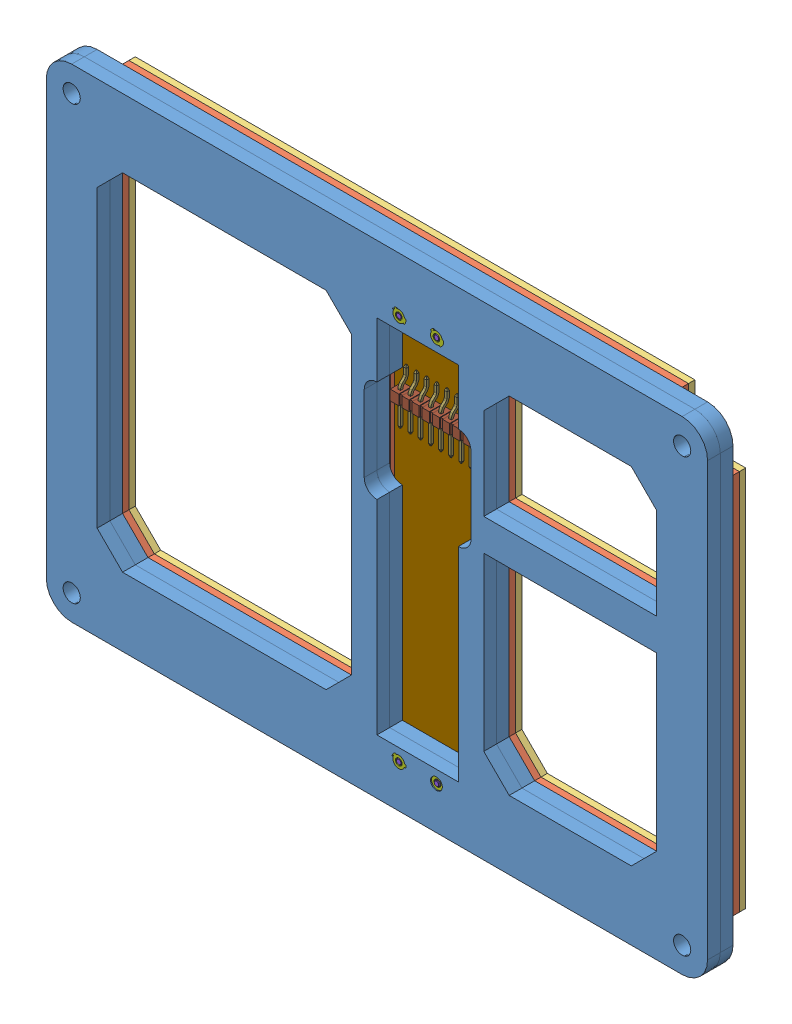
SolidWorks assembly IFEI Panel, configuration Default. Lengths in mm.
Overall size (165.1 120.65 15.95).
35 component instances, 12 part files, 29 mates.
Components (placement in the parent):
- IFEI Backplate-1: IFEI Backplate [Default] at (0 0 -3.175) size (165.1 120.65 3.17)
- IFEI Backplate-2: IFEI Backplate [Default] at origin size (165.1 120.65 3.17)
- IFEI Lightplate-1: IFEI Lightplate [Default] at (0 0 -6.35) x (-1 0 0) z (0 0 -1) size (165.1 120.65 1.59)
- IFEI Legend Plate-1: IFEI Legend Plate [Default] at (0 0 -7.9375) x (-1 0 0) z (0 0 -1) size (165.1 120.65 1.59)
- IFEI Button Bezel-1: IFEI Button Bezel [Default] at (0 0 -9.525) x (-1 0 0) z (0 0 -1) size (20.32 100.33 6.35)
- IFEI Button-1: IFEI Button [MODE] at (0 0 -12.7) x (-1 0 0) z (0 0 -1) size (15.49 9.14 3.17)
- IFEI Button Retainer-1: IFEI Button Retainer [Default] at (0 0 -11.1125) size (18.03 11.68 2.86)
- IFEI Button-2: IFEI Button [QTY] at (0 15.24 -12.7) x (-1 0 0) z (0 0 -1) size (15.49 9.14 3.17)
- IFEI Button-3: IFEI Button [ARROW] at (0 30.48 -12.7) x (-1 0 0) z (0 0 -1) size (15.49 9.14 3.17)
- IFEI Button-4: IFEI Button [ARROW] at (185.42 -154.178 -12.7) x (1 0 0) z (0 0 -1) size (15.49 9.14 3.17)
- IFEI Button-5: IFEI Button [ZONE] at (0 60.96 -12.7) x (-1 0 0) z (0 0 -1) size (15.49 9.14 3.17)
- IFEI Button-6: IFEI Button [ET] at (0 76.2 -12.7) x (-1 0 0) z (0 0 -1) size (15.49 9.14 3.17)
- IFEI Button Retainer-2: IFEI Button Retainer [Default] at (0 15.24 -11.1125) size (18.03 11.68 2.86)
- IFEI Button Retainer-3: IFEI Button Retainer [Default] at (0 30.48 -11.1125) size (18.03 11.68 2.86)
- IFEI Button Retainer-4: IFEI Button Retainer [Default] at (0 45.72 -11.1125) size (18.03 11.68 2.86)
- IFEI Button Retainer-5: IFEI Button Retainer [Default] at (0 60.96 -11.1125) size (18.03 11.68 2.86)
- IFEI Button Retainer-6: IFEI Button Retainer [Default] at (0 76.2 -11.1125) size (18.03 11.68 2.86)
- 93365A102__BRASS HEAT-SET INSERT FOR PLASTICS_0-80-1: 93365A102__BRASS HEAT-SET INSERT FOR PLASTICS_0-80 [Default] at (97.409 -110.0455 -3.175) x (-1 0 0) z (0 -1 0) size (3.58 3.01 3.58)
- 91249A024 - PHS, 0-80 X .50, 18-8, BLACK-OXIDE-1: 91249A024 - PHS, 0-80 X .50, 18-8, BLACK-OXIDE [91249A024] at (97.409 -110.0455 0) x (0.892261 0.451519 0) z (0 0 -1) size (2.95 2.95 13.84)
- 93365A102__BRASS HEAT-SET INSERT FOR PLASTICS_0-80-2: 93365A102__BRASS HEAT-SET INSERT FOR PLASTICS_0-80 [Default] at (88.011 -110.0455 0) x (0.27024 -0.962793 0) z (-0.962793 -0.27024 0) size (3.58 3.01 3.58)
- 91249A024 - PHS, 0-80 X .50, 18-8, BLACK-OXIDE-2: 91249A024 - PHS, 0-80 X .50, 18-8, BLACK-OXIDE [91249A024] at (88.011 -110.0455 0) x (0.615714 -0.78797 0) z (0 0 -1) size (2.95 2.95 13.84)
- 93365A102__BRASS HEAT-SET INSERT FOR PLASTICS_0-80-3: 93365A102__BRASS HEAT-SET INSERT FOR PLASTICS_0-80 [Default] at (97.409 -13.6525 0) x (0.414026 -0.910265 0) z (-0.910265 -0.414026 0) size (3.58 3.01 3.58)
- 91249A024 - PHS, 0-80 X .50, 18-8, BLACK-OXIDE-3: 91249A024 - PHS, 0-80 X .50, 18-8, BLACK-OXIDE [91249A024] at (97.409 -13.6525 0) x (0.488231 -0.872714 0) z (0 0 -1) size (2.95 2.95 13.84)
- 93365A102__BRASS HEAT-SET INSERT FOR PLASTICS_0-80-4: 93365A102__BRASS HEAT-SET INSERT FOR PLASTICS_0-80 [Default] at (88.011 -13.6525 0) x (-0.983471 -0.181065 0) z (-0.181065 0.983471 0) size (3.58 3.01 3.58)
- 91249A024 - PHS, 0-80 X .50, 18-8, BLACK-OXIDE-4: 91249A024 - PHS, 0-80 X .50, 18-8, BLACK-OXIDE [91249A024] at (88.011 -13.6525 0) x (0.728364 0.685191 0) z (0 0 -1) size (2.95 2.95 13.84)
- IFEI PCB-1: IFEI PCB [Default] at (0 0 -6.35) x (-1 0 0) z (0 0 -1) size (24.32 104.33 1.59)
- GX06400 - SWITCH, DOME, SNAPTRON, 6.3mm DIA, 400gf-1: GX06400 - SWITCH, DOME, SNAPTRON, 6.3mm DIA, 400gf [Default] at (92.71 -99.949 -7.9375) x (-0.707107 -0.707107 0) z (0.707107 -0.707107 0) size (6.3 0.36 6.3)
- GX06400 - SWITCH, DOME, SNAPTRON, 6.3mm DIA, 400gf-2: GX06400 - SWITCH, DOME, SNAPTRON, 6.3mm DIA, 400gf [Default] at (92.71 -84.709 -7.9375) x (-0.707107 -0.707107 0) z (0.707107 -0.707107 0) size (6.3 0.36 6.3)
- GX06400 - SWITCH, DOME, SNAPTRON, 6.3mm DIA, 400gf-3: GX06400 - SWITCH, DOME, SNAPTRON, 6.3mm DIA, 400gf [Default] at (92.71 -69.469 -7.9375) x (-0.707107 -0.707107 0) z (0.707107 -0.707107 0) size (6.3 0.36 6.3)
- GX06400 - SWITCH, DOME, SNAPTRON, 6.3mm DIA, 400gf-4: GX06400 - SWITCH, DOME, SNAPTRON, 6.3mm DIA, 400gf [Default] at (92.71 -54.229 -7.9375) x (-0.707107 -0.707107 0) z (0.707107 -0.707107 0) size (6.3 0.36 6.3)
- GX06400 - SWITCH, DOME, SNAPTRON, 6.3mm DIA, 400gf-5: GX06400 - SWITCH, DOME, SNAPTRON, 6.3mm DIA, 400gf [Default] at (92.71 -38.989 -7.9375) x (-0.707107 -0.707107 0) z (0.707107 -0.707107 0) size (6.3 0.36 6.3)
- GX06400 - SWITCH, DOME, SNAPTRON, 6.3mm DIA, 400gf-6: GX06400 - SWITCH, DOME, SNAPTRON, 6.3mm DIA, 400gf [Default] at (92.71 -23.749 -7.9375) x (-0.707107 -0.707107 0) z (0.707107 -0.707107 0) size (6.3 0.36 6.3)
- TSM_108_01_T_SH-1: TSM_108_01_T_SH [Default] at (92.71 -35.084 -6.35) x (1 0 0) z (0 -1 0) size (20.32 3.05 12.95)
  - _TSM_108_01_SH_body_2-1: _TSM_108_01_SH_body_2 [Default] at (0 1.524 0) size (20.32 3.05 2.54)
  - _T_1S6_08__01_8_SH__4-1: _T_1S6_08__01_8_SH__4 [Default] at (0 0 -5.842) x (1 0 0) z (0 -1 0) size (18.42 12.95 2.1)
Mates (geometry in assembly coordinates):
- Coincident60: coincident: plane of IFEI Backplate-2 through (6.35 -120.65 -3.175) normal (0 -1 0); plane of IFEI Backplate-1 through (6.35 -120.65 -6.35) normal (0 -1 0)
- Coincident61: coincident: plane of IFEI Backplate-2 through (0 -6.35 -3.175) normal (-1 0 0); plane of IFEI Backplate-1 through (0 -6.35 -6.35) normal (-1 0 0)
- Coincident62: coincident: plane of IFEI Backplate-2 through (6.35 -114.3 -3.175) normal (0 0 -1); plane of IFEI Backplate-1 through (6.35 -114.3 -3.175) normal (0 0 1)
- Coincident66: coincident: plane of IFEI Lightplate-1 through (152.4 -120.65 -7.9375) normal (0 -1 0); plane of IFEI Legend Plate-1 through (152.4 -120.65 -9.525) normal (0 -1 0)
- Coincident67: coincident: plane of IFEI Lightplate-1 through (0 -107.95 -7.9375) normal (-1 0 0); plane of IFEI Legend Plate-1 through (0 -107.95 -9.525) normal (-1 0 0)
- Coincident68: coincident: plane of IFEI Lightplate-1 through (6.35 -6.35 -7.9375) normal (0 0 -1); plane of IFEI Legend Plate-1 through (6.35 -6.35 -7.9375) normal (0 0 1)
- Coincident72: coincident: plane of IFEI Button Bezel-1 through (0 0 -12.7) normal (0 0 -1); plane of 91249A024 - PHS, 0-80 X .50, 18-8, BLACK-OXIDE-1 through (97.409 -110.0455 -12.7) normal (0 0 1)
- Concentric40: concentric: cylinder of IFEI Button Bezel-1 through (88.011 -110.0455 -12.7) axis (0 0 -1) radius 0.9271; cone of 93365A102__BRASS HEAT-SET INSERT FOR PLASTICS_0-80-2 through (88.011 -110.0455 -1.11) axis (0 0 -1)
- Coincident76: coincident: plane of IFEI Button Bezel-1 through (0 0 -12.7) normal (0 0 -1); plane of 91249A024 - PHS, 0-80 X .50, 18-8, BLACK-OXIDE-2 through (88.011 -110.0455 -12.7) normal (0 0 1)
- Concentric42: concentric: cylinder of IFEI Button Bezel-1 through (97.409 -13.6525 -12.7) axis (0 0 -1) radius 0.9271; cone of 93365A102__BRASS HEAT-SET INSERT FOR PLASTICS_0-80-3 through (97.409 -13.6525 -1.11) axis (0 0 -1)
- Coincident78: coincident: plane of IFEI Button Bezel-1 through (0 0 -12.7) normal (0 0 -1); plane of 91249A024 - PHS, 0-80 X .50, 18-8, BLACK-OXIDE-3 through (97.409 -13.6525 -12.7) normal (0 0 1)
- Coincident80: coincident: plane of IFEI Button Bezel-1 through (0 0 -12.7) normal (0 0 -1); plane of 91249A024 - PHS, 0-80 X .50, 18-8, BLACK-OXIDE-4 through (88.011 -13.6525 -12.7) normal (0 0 1)
- Symmetric2: symmetric aligned: plane of IFEI Button Retainer-1 through (101.727 -94.107 -9.525) normal (0 1 0); plane of GX06400 - SWITCH, DOME, SNAPTRON, 6.3mm DIA, 400gf-1 through (83.693 -105.791 -9.525) normal (0 -1 0); plane of IFEI Button Retainer-1 through (92.71 -99.949 -7.9375) normal (0 1 0)
- ProfileCenter1: profile center anti-aligned: plane of IFEI Button-4 through (185.42 -154.178 -11.1125) normal (0 0 1); plane of IFEI Button Retainer-4 through (0 45.72 -11.1125) normal (0 0 -1)
- Concentric37: concentric: cone of IFEI Backplate-2 through (97.409 -110.0455 -3.175) axis (0 0 1); cone of 93365A102__BRASS HEAT-SET INSERT FOR PLASTICS_0-80-1 through (97.409 -110.0455 -2.065) axis (0 0 1)
- Coincident71: coincident: plane of IFEI Backplate-2 through (6.35 -114.3 -3.175) normal (0 0 -1); plane of 93365A102__BRASS HEAT-SET INSERT FOR PLASTICS_0-80-1 through (99.1997 -110.0455 -3.175) normal (0 0 -1)
- Concentric38: concentric: circle of 93365A102__BRASS HEAT-SET INSERT FOR PLASTICS_0-80-1; cylinder of 91249A024 - PHS, 0-80 X .50, 18-8, BLACK-OXIDE-1 through (97.409 -110.0455 0) axis (0 0 1) radius 1.4732
- Concentric39: concentric: circle of 93365A102__BRASS HEAT-SET INSERT FOR PLASTICS_0-80-2; cylinder of 91249A024 - PHS, 0-80 X .50, 18-8, BLACK-OXIDE-2 through (88.011 -110.0455 0) axis (0 0 1) radius 1.4732
- Coincident75: coincident: plane of IFEI Backplate-2 through (6.35 -114.3 0) normal (0 0 1); plane of 93365A102__BRASS HEAT-SET INSERT FOR PLASTICS_0-80-2 through (87.5271 -108.3214 0) normal (0 0 1)
- Concentric41: concentric: circle of 93365A102__BRASS HEAT-SET INSERT FOR PLASTICS_0-80-3; cylinder of 91249A024 - PHS, 0-80 X .50, 18-8, BLACK-OXIDE-3 through (97.409 -13.6525 0) axis (0 0 1) radius 1.4732
- Coincident77: coincident: plane of IFEI Backplate-2 through (6.35 -114.3 0) normal (0 0 1); plane of 93365A102__BRASS HEAT-SET INSERT FOR PLASTICS_0-80-3 through (96.6676 -12.0225 0) normal (0 0 1)
- Concentric43: concentric: circle of 93365A102__BRASS HEAT-SET INSERT FOR PLASTICS_0-80-4; cylinder of 91249A024 - PHS, 0-80 X .50, 18-8, BLACK-OXIDE-4 through (88.011 -13.6525 0) axis (0 0 1) radius 1.4732
- Concentric44: concentric: cone of IFEI Backplate-2 through (88.011 -13.6525 -3.175) axis (0 0 1); cone of 93365A102__BRASS HEAT-SET INSERT FOR PLASTICS_0-80-4 through (88.011 -13.6525 -1.11) axis (0 0 -1)
- Coincident79: coincident: plane of IFEI Backplate-2 through (6.35 -114.3 0) normal (0 0 1); plane of 93365A102__BRASS HEAT-SET INSERT FOR PLASTICS_0-80-4 through (89.7721 -13.3283 0) normal (0 0 1)
- Coincident81: coincident anti-aligned: plane of IFEI PCB-1 through (0 0 -7.9375) normal (0 0 -1); plane of GX06400 - SWITCH, DOME, SNAPTRON, 6.3mm DIA, 400gf-1 through (92.71 -99.949 -7.9375) normal (0 0 1)
- Symmetric1: symmetric aligned: plane of IFEI PCB-1 through (104.87 -9.684 -7.9375) normal (1 0 0); plane of GX06400 - SWITCH, DOME, SNAPTRON, 6.3mm DIA, 400gf-1 through (80.55 -114.014 -7.9375) normal (-1 0 0); plane of IFEI PCB-1 through (92.71 -99.949 -7.9375) normal (1 0 0)
- Coincident82: coincident anti-aligned: plane of IFEI PCB-1 through (0 0 -6.35) normal (0 0 1); plane of TSM_108_01_T_SH-1/_TSM_108_01_SH_body_2-1 through (82.55 -36.354 -6.35) normal (0 0 -1)
- Width5: width anti-aligned: plane of IFEI PCB-1 through (80.55 -114.014 -7.9375) normal (-1 0 0); plane of TSM_108_01_T_SH-1/_TSM_108_01_SH_body_2-1 through (104.87 -9.684 -7.9375) normal (1 0 0); plane of IFEI PCB-1 through (102.87 -36.354 -6.35) normal (1 0 0); plane of TSM_108_01_T_SH-1/_TSM_108_01_SH_body_2-1 through (82.55 -36.354 -3.302) normal (-1 0 0)
- Distance8: distance = 25.4 mm anti-aligned: plane of TSM_108_01_T_SH-1 through (92.71 -35.084 -6.35) normal (0 -1 0); plane of IFEI PCB-1 through (80.55 -9.684 -7.9375) normal (0 1 0)
